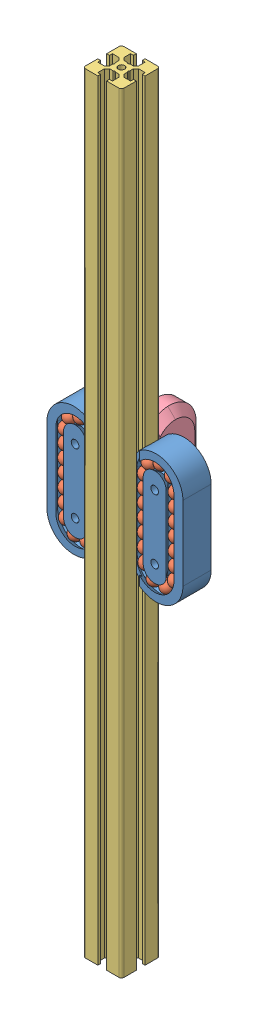
SolidWorks assembly Linear Bearing Assembly, configuration Default. Lengths in mm.
Overall size (53 300 34.02).
42 component instances, 4 part files, 21 mates.
Components (placement in the parent):
- Recurculating Linear Bearing-1: Recurculating Linear Bearing [Default] at (1989.7483 27.566 3349.3533) size (21 50 11)
- .1875in Bearing-1: .1875in Bearing [Default] at (1.2591 45.9577 47.3713) x (0.426239 -0.533422 0.730604) z (-0.712226 -0.695827 -0.092514) size (5.25 4.76 4.76)
- .1875in Bearing-2: .1875in Bearing [Default] at (10.3263 46.0341 47.3713) x (0.131711 0.893667 0.428966) z (0.756892 0.188779 -0.625682) size (5.25 4.76 4.76)
- .1875in Bearing-3: .1875in Bearing [Default] at (11.8258 41.4503 47.3713) x (0.996107 0.074205 0.047596) z (-0.053362 0.07777 0.995542) size (5.25 4.76 4.76)
- .1875in Bearing-4: .1875in Bearing [Default] at (-0.1742 41.2088 47.3713) x (0.965724 0.201323 -0.163847) z (0.171337 -0.020237 0.985005) size (5.25 4.76 4.76)
- .1875in Bearing-5: .1875in Bearing [Default] at (11.8258 26.6114 47.3713) x (0.955936 0.113097 -0.270917) z (0.272625 0.000374 0.96212) size (5.25 4.76 4.76)
- .1875in Bearing-6: .1875in Bearing [Default] at (11.8258 31.5957 47.3713) x (0.787723 0.536576 -0.30262) z (0.096537 -0.592695 -0.799621) size (5.25 4.76 4.76)
- .1875in Bearing-7: .1875in Bearing [Default] at (-0.1742 31.2247 47.3713) x (0.643785 0.342618 -0.684217) z (0.757996 -0.163078 0.631544) size (5.25 4.76 4.76)
- .1875in Bearing-8: .1875in Bearing [Default] at (-0.1742 36.2457 47.3713) x (0.985028 0.127482 -0.116049) z (0.123771 -0.054399 0.990819) size (5.25 4.76 4.76)
- .1875in Bearing-9: .1875in Bearing [Default] at (-0.1742 26.3773 47.3713) x (0.891675 0.320064 -0.320117) z (-0.046367 0.768023 0.638742) size (5.25 4.76 4.76)
- .1875in Bearing-10: .1875in Bearing [Default] at (11.8258 16.6272 47.3713) x (0.683742 0.374784 -0.626126) z (0.698699 -0.088708 0.709895) size (5.25 4.76 4.76)
- .1875in Bearing-11: .1875in Bearing [Default] at (8.4051 7.6487 47.3713) x (0.980177 0.055974 -0.190055) z (0.164355 0.305971 0.937747) size (5.25 4.76 4.76)
- .1875in Bearing-12: .1875in Bearing [Default] at (0.1232 11.2003 47.3713) x (-0.059086 -0.816886 0.573764) z (-0.323619 -0.528053 -0.785131) size (5.25 4.76 4.76)
- .1875in Bearing-13: .1875in Bearing [Default] at (5.7045 48.0648 47.3713) x (0.995784 0.05551 0.073025) z (-0.04295 -0.421281 0.905913) size (5.25 4.76 4.76)
- .1875in Bearing-14: .1875in Bearing [Default] at (-0.1742 21.2754 47.3713) x (0.871049 -0.097593 -0.481404) z (0.491185 0.179977 0.852259) size (5.25 4.76 4.76)
- .1875in Bearing-15: .1875in Bearing [Default] at (11.8258 36.5729 47.3713) x (0.97709 0.211493 -0.023784) z (0.02933 -0.023125 0.999302) size (5.25 4.76 4.76)
- .1875in Bearing-16: .1875in Bearing [Default] at (11.8258 21.6721 47.3713) x (0.571866 0.818465 0.055542) z (0.806301 -0.548309 -0.221891) size (5.25 4.76 4.76)
- .1875in Bearing-17: .1875in Bearing [Default] at (-0.1742 16.2516 47.3713) x (0.871598 0.245724 -0.42419) z (-0.042974 0.90027 0.433206) size (5.25 4.76 4.76)
- .1875in Bearing-18: .1875in Bearing [Default] at (11.6179 11.5005 47.3713) x (0.46475 -0.878362 -0.111746) z (0.377247 0.08225 0.922453) size (5.25 4.76 4.76)
- .1875in Bearing-19: .1875in Bearing [Default] at (3.4791 7.544 47.3713) x (0.480586 -0.547037 -0.685411) z (0.746497 0.665345 -0.007604) size (5.25 4.76 4.76)
- .1875in Bearing-20: .1875in Bearing [Default] at (34.2465 7.6487 47.3713) x (-0.980177 0.055974 -0.190055) z (0.164355 -0.305971 -0.937747) size (5.25 4.76 4.76)
- .1875in Bearing-21: .1875in Bearing [Default] at (42.8258 16.2516 47.3713) x (-0.871598 0.245724 -0.42419) z (-0.042974 -0.90027 -0.433206) size (5.25 4.76 4.76)
- .1875in Bearing-22: .1875in Bearing [Default] at (42.8258 21.2754 47.3713) x (-0.871049 -0.097593 -0.481404) z (0.491185 -0.179977 -0.852259) size (5.25 4.76 4.76)
- .1875in Bearing-23: .1875in Bearing [Default] at (31.0336 11.5005 47.3713) x (-0.46475 -0.878362 -0.111746) z (0.377247 -0.08225 -0.922453) size (5.25 4.76 4.76)
- .1875in Bearing-24: .1875in Bearing [Default] at (39.1725 7.544 47.3713) x (-0.480586 -0.547037 -0.685411) z (0.746497 -0.665345 0.007604) size (5.25 4.76 4.76)
- .1875in Bearing-25: .1875in Bearing [Default] at (42.5283 11.2003 47.3713) x (0.059086 -0.816886 0.573764) z (-0.323619 0.528053 0.785131) size (5.25 4.76 4.76)
- .1875in Bearing-26: .1875in Bearing [Default] at (36.9471 48.0648 47.3713) x (-0.995784 0.05551 0.073025) z (-0.04295 0.421281 -0.905913) size (5.25 4.76 4.76)
- .1875in Bearing-27: .1875in Bearing [Default] at (30.8258 36.5729 47.3713) x (-0.97709 0.211493 -0.023784) z (0.02933 0.023125 -0.999302) size (5.25 4.76 4.76)
- .1875in Bearing-28: .1875in Bearing [Default] at (30.8258 21.6721 47.3713) x (-0.571866 0.818465 0.055542) z (0.806301 0.548309 0.221891) size (5.25 4.76 4.76)
- .1875in Bearing-29: .1875in Bearing [Default] at (30.8258 16.6272 47.3713) x (-0.683742 0.374784 -0.626126) z (0.698699 0.088708 -0.709895) size (5.25 4.76 4.76)
- Recurculating Linear Bearing-2: Recurculating Linear Bearing [Default] at (-1947.0968 27.566 3349.3533) x (-1 0 0) z (0 0 1) size (21 50 11)
- .1875in Bearing-30: .1875in Bearing [Default] at (42.8258 31.2247 47.3713) x (-0.643785 0.342618 -0.684217) z (0.757996 0.163078 -0.631544) size (5.25 4.76 4.76)
- .1875in Bearing-31: .1875in Bearing [Default] at (30.8258 26.6114 47.3713) x (-0.955936 0.113097 -0.270917) z (0.272625 -0.000374 -0.96212) size (5.25 4.76 4.76)
- .1875in Bearing-32: .1875in Bearing [Default] at (30.8258 31.5957 47.3713) x (-0.787723 0.536576 -0.30262) z (0.096537 0.592695 0.799621) size (5.25 4.76 4.76)
- .1875in Bearing-33: .1875in Bearing [Default] at (42.8258 26.3773 47.3713) x (-0.891675 0.320064 -0.320117) z (-0.046367 -0.768023 -0.638742) size (5.25 4.76 4.76)
- .1875in Bearing-34: .1875in Bearing [Default] at (42.8258 41.2088 47.3713) x (-0.965724 0.201323 -0.163847) z (0.171337 0.020237 -0.985005) size (5.25 4.76 4.76)
- .1875in Bearing-35: .1875in Bearing [Default] at (32.3252 46.0341 47.3713) x (-0.131711 0.893667 0.428966) z (0.756892 -0.188779 0.625682) size (5.25 4.76 4.76)
- .1875in Bearing-36: .1875in Bearing [Default] at (42.8258 36.2457 47.3713) x (-0.985028 0.127482 -0.116049) z (0.123771 0.054399 -0.990819) size (5.25 4.76 4.76)
- .1875in Bearing-37: .1875in Bearing [Default] at (41.3925 45.9577 47.3713) x (-0.426239 -0.533422 0.730604) z (-0.712226 0.695827 0.092514) size (5.25 4.76 4.76)
- .1875in Bearing-38: .1875in Bearing [Default] at (30.8258 41.4503 47.3713) x (-0.996107 0.074205 0.047596) z (-0.053362 -0.07777 -0.995542) size (5.25 4.76 4.76)
- MISUMI 15 - 300mm-1: MISUMI 15 - 300mm [Default] at (21.371 -126.3405 47.3992) size (15 300 15)
- Recurculating Linear Bearing Center-1: Recurculating Linear Bearing Center [Default] at (-3280.611 27.8522 2015.8218) x (0 0 1) z (-1 0 0) size (21.02 50.08 11.92)
Mates (geometry in assembly coordinates):
- PathMate22: path: point of .1875in Bearing-6; curve of Recurculating Linear Bearing-1; curve of Recurculating Linear Bearing-1
- PathMate23: path: point of .1875in Bearing-13; curve of Recurculating Linear Bearing-1; curve of Recurculating Linear Bearing-1
- PathMate24: path: point of .1875in Bearing-1; curve of Recurculating Linear Bearing-1; curve of Recurculating Linear Bearing-1
- PathMate25: path: point of .1875in Bearing-3; curve of Recurculating Linear Bearing-1; curve of Recurculating Linear Bearing-1
- PathMate26: path: point of .1875in Bearing-16; curve of Recurculating Linear Bearing-1; curve of Recurculating Linear Bearing-1
- PathMate27: path: point of .1875in Bearing-15; curve of Recurculating Linear Bearing-1; curve of Recurculating Linear Bearing-1
- PathMate28: path: point of .1875in Bearing-5; curve of Recurculating Linear Bearing-1; curve of Recurculating Linear Bearing-1
- PathMate29: path: point of .1875in Bearing-10; curve of Recurculating Linear Bearing-1; curve of Recurculating Linear Bearing-1
- PathMate30: path: point of .1875in Bearing-19; curve of Recurculating Linear Bearing-1; curve of Recurculating Linear Bearing-1
- PathMate31: path: point of .1875in Bearing-18; curve of Recurculating Linear Bearing-1; curve of Recurculating Linear Bearing-1
- PathMate32: path: point of .1875in Bearing-17; curve of Recurculating Linear Bearing-1; curve of Recurculating Linear Bearing-1
- PathMate33: path: point of .1875in Bearing-11; curve of Recurculating Linear Bearing-1; curve of Recurculating Linear Bearing-1
- PathMate34: path: point of .1875in Bearing-12; curve of Recurculating Linear Bearing-1; curve of Recurculating Linear Bearing-1
- PathMate35: path: point of .1875in Bearing-9; curve of Recurculating Linear Bearing-1; curve of Recurculating Linear Bearing-1
- PathMate36: path: point of .1875in Bearing-8; curve of Recurculating Linear Bearing-1; curve of Recurculating Linear Bearing-1
- PathMate37: path: point of .1875in Bearing-4; curve of Recurculating Linear Bearing-1; curve of Recurculating Linear Bearing-1
- PathMate38: path: point of .1875in Bearing-14; curve of Recurculating Linear Bearing-1; curve of Recurculating Linear Bearing-1
- PathMate39: path: point of .1875in Bearing-7; curve of Recurculating Linear Bearing-1; curve of Recurculating Linear Bearing-1
- PathMate40: path: point of .1875in Bearing-2; curve of Recurculating Linear Bearing-1; curve of Recurculating Linear Bearing-1
- Distance3: distance = 2 mm anti-aligned: plane of MISUMI 15 - 300mm-1 through (27.871 173.6595 39.8992) normal (0 0 -1); plane of Recurculating Linear Bearing Center-1 through (22.621 27.8522 37.8992) normal (0 0 1)
- Distance4: distance = 0.45 mm anti-aligned: plane of Recurculating Linear Bearing Center-1 through (22.621 27.8522 31.8992) normal (1 0 0); plane of MISUMI 15 - 300mm-1 through (23.071 173.6595 39.8992) normal (-1 0 0)
